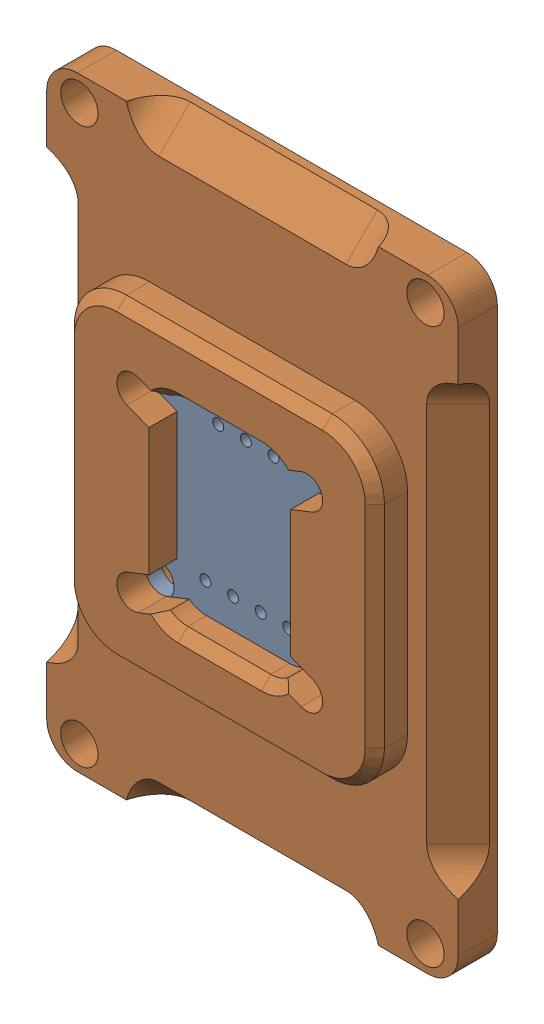
SolidWorks assembly Encoder_1__1, configuration Default. Lengths in mm.
Overall size (37.8 55.6 6.6).
2 component instances, 2 part files, 0 mates.
Components (placement in the parent):
- AS5600_1-1: AS5600_1 [Default] at (0 148.56 137.1) x (1 0 0) z (0 1 0) size (23 3.5 23)
- EncoderHousing_1-1: EncoderHousing_1 [Default] at (0 148.56 134.8) x (1 0 0) z (0 0 -1) size (37.8 55.6 6.6)
